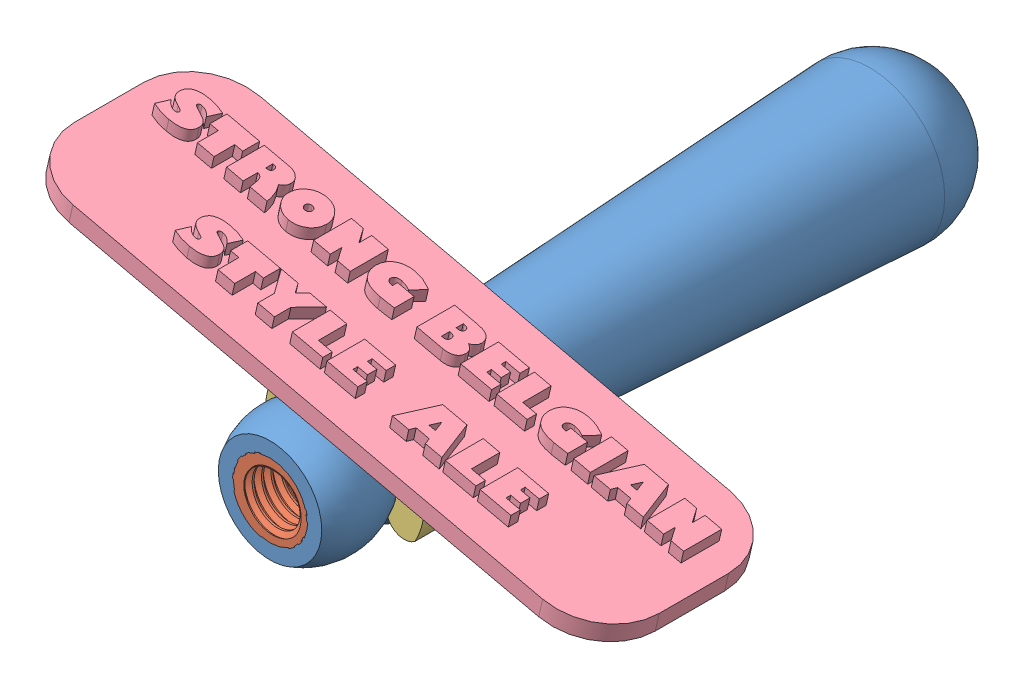
SolidWorks assembly Tap Handle Assembly, configuration Default. Lengths in mm.
Overall size (100.18 40.54 114.91).
4 component instances, 4 part files, 7 mates.
Components (placement in the parent):
- Tap Handle-1: Tap Handle [Default] at (73.5875 69.3045 122.0416) size (25.44 25.44 114.32)
- Tap Handle Thread-1: Tap Handle Thread [Default] at (73.5875 69.3045 102.9916) size (12.7 12.7 20.24)
- Tap Sign-1: Tap Sign [Default] at (73.5875 69.3045 96.6416) x (0.975171 -0.221455 0) z (0 0 1) size (27 18.25 12.7)
- Tap Sign Beer Name-1: Tap Sign Beer Name [Default] at (76.2938 80.9955 103.1416) x (0.975171 -0.221455 0) z (0 0 1) size (101.6 5 31.75)
Mates (geometry in assembly coordinates):
- Coincident1: coincident aligned: plane of Tap Handle-1 through (73.5875 69.3045 122.0416) normal (0 0 1); plane of Tap Handle Thread-1 through (73.5875 69.3045 122.0416) normal (0 0 1)
- Concentric2: concentric aligned: circle of Tap Handle-1; circle of Tap Handle Thread-1
- Concentric4: concentric anti-aligned: circle of Tap Handle-1; circle of Tap Sign-1
- Coincident2: coincident anti-aligned: circle of Tap Handle-1; plane of Tap Sign-1 through (62.8007 69.9572 96.6416) normal (0 0 -1)
- Coincident20: coincident: plane of Tap Sign-1 through (62.8007 69.9572 96.6416) normal (0 0 -1); plane of Tap Sign Beer Name-1 through (77.7606 82.7133 96.6416) normal (0 0 1)
- Coincident21: coincident: plane of Tap Sign-1 through (75.2698 81.228 109.3416) normal (-0.975171 0.221455 0); plane of Tap Sign Beer Name-1 through (75.7127 83.1784 109.6416) normal (0.975171 -0.221455 0)
- Coincident22: coincident anti-aligned: plane of Tap Sign-1 through (70.2139 82.3762 109.3416) normal (0.221455 0.975171 0); plane of Tap Sign Beer Name-1 through (36.5068 90.0309 97.2666) normal (-0.221455 -0.975171 0)
